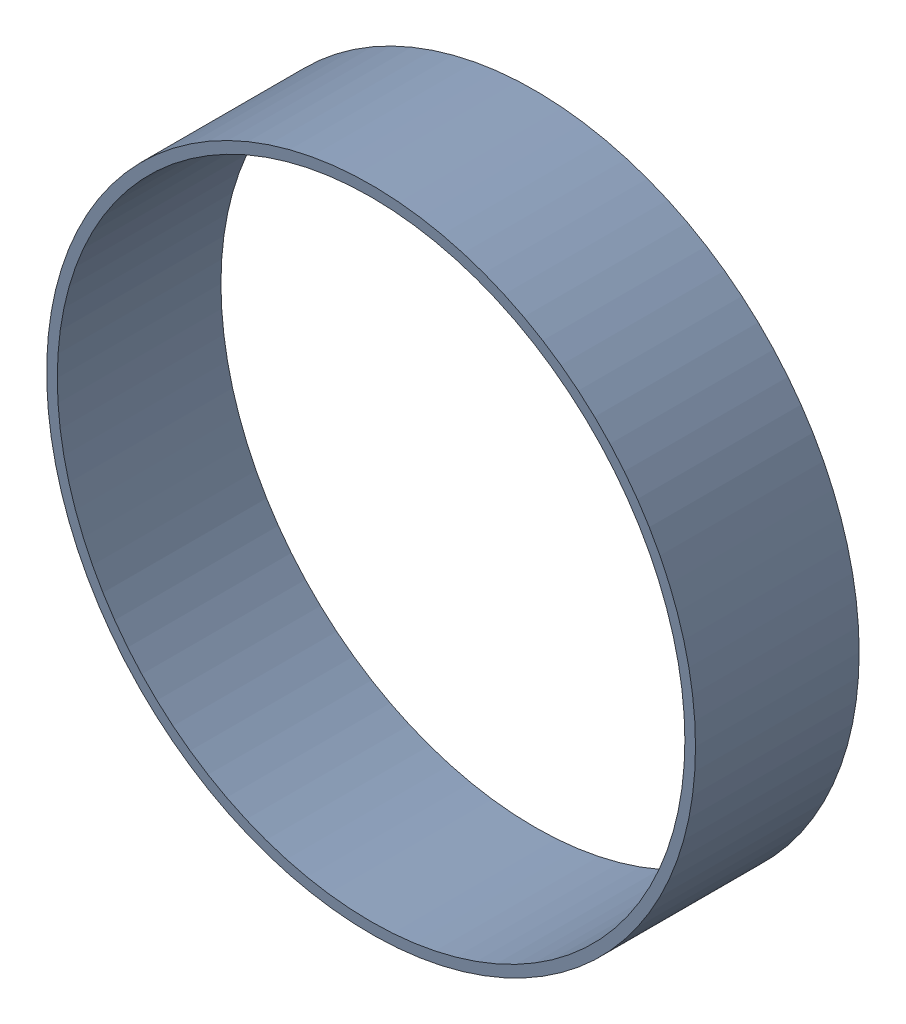
SolidWorks assembly Pad Free-4(5.842mm,62.992mm) on Multi-Layer, configuration Predeterminado. Lengths in mm.
Overall size (1.55 1.55 0.39).
2 component instances, 1 part files, 0 mates.
Components (placement in the parent):
- Pad Hole-2-1: Pad Hole-2 [Predeterminado] at (5.842 62.992 -0.4013) size (1.55 1.55 0.39)
  - Pad Hole-Part-1-2-1: Pad Hole-Part-1-2 [Predeterminado] at origin size (1.55 1.55 0.39)
